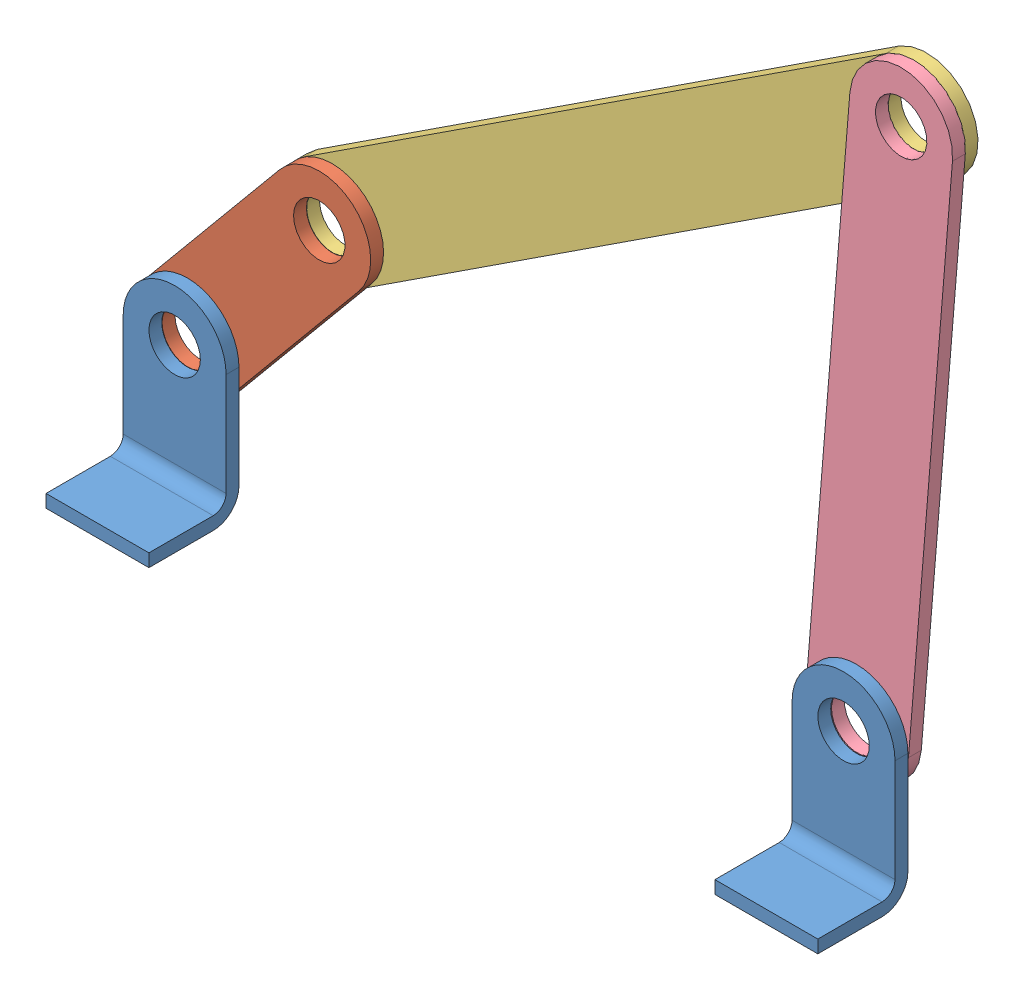
SolidWorks assembly 4-Bar_Link, configuration Default. Lengths in mm.
Overall size (332.94 286.99 45.2).
5 component instances, 4 part files, 10 mates.
Components (placement in the parent):
- Support-1: Support [Default] at origin size (40 70 35)
- Support-2: Support [Default] at (260 0 0) size (40 70 35)
- Link-1-1: Link-1 [Default] at (-0.6014 60.9195 -5.1) x (0.638916 0.769277 0) z (0 0 1) size (120 40 5)
- Link-2-1: Link-2 [Default] at (214.8303 219.8088 -10.2) x (0.83696 0.547263 0) z (0 0 1) size (310 40 5)
- Link-4-1: Link-4 [Default] at (242.6409 91.4689 -5.3) x (-0.081393 -0.996682 0) z (0 0 1) size (250 40 5)
Mates (geometry in assembly coordinates):
- Coincident1: coincident aligned: plane of Part1-1 through (-20 40 5) normal (0 0 1); plane of Part1-2 through (240 40 5) normal (0 0 1)
- Coincident2: coincident aligned: plane of Part1-1 through (-76.4005 -10 35) normal (0 -1 0); plane of Part1-2 through (183.5995 -10 35) normal (0 -1 0)
- Distance1: distance = 220 mm anti-aligned: plane of Part1-2 through (220 0 5) normal (-1 0 0); plane of Part1-1 through (0 40 5) normal (1 0 0)
- Concentric1: concentric aligned: cylinder of Part1-1 through (-20 40 0) axis (0 0 1) radius 10; cylinder of Part2-1 through (-20 40 -5.1) axis (0 0 1) radius 10
- Distance2: distance = 0.1 mm anti-aligned: plane of Part1-1 through (-20 40 0) normal (0 0 -1); plane of Part2-1 through (31.1133 101.5421 -0.1) normal (0 0 1)
- Concentric2: concentric aligned: cylinder of Part2-1 through (6.748 115.3959 -5.1) axis (0 0 1) radius 10; cylinder of Link-2-1 through (6.748 115.3959 -10.2) axis (0 0 1) radius 10
- Distance3: distance = 0.1 mm anti-aligned: plane of Part2-1 through (31.1133 101.5421 -5.1) normal (0 0 -1); plane of Part3-1 through (257.0926 249.3032 -5.2) normal (0 0 1)
- Concentric3: concentric aligned: cylinder of Link-2-1 through (240.8039 249.9985 -10.2) axis (0 0 1) radius 10; cylinder of Link-4-1 through (240.8039 249.9985 -5.3) axis (0 0 1) radius 10
- Distance4: distance = 0.1 mm anti-aligned: plane of Part3-1 through (257.0926 249.3032 -5.2) normal (0 0 1); plane of Part4-1 through (240 40 -5.3) normal (0 0 -1)
- Concentric4: concentric aligned: cylinder of Part1-2 through (240 40 0) axis (0 0 1) radius 10; cylinder of Link-4-1 through (240 40 -5.3) axis (0 0 1) radius 10
